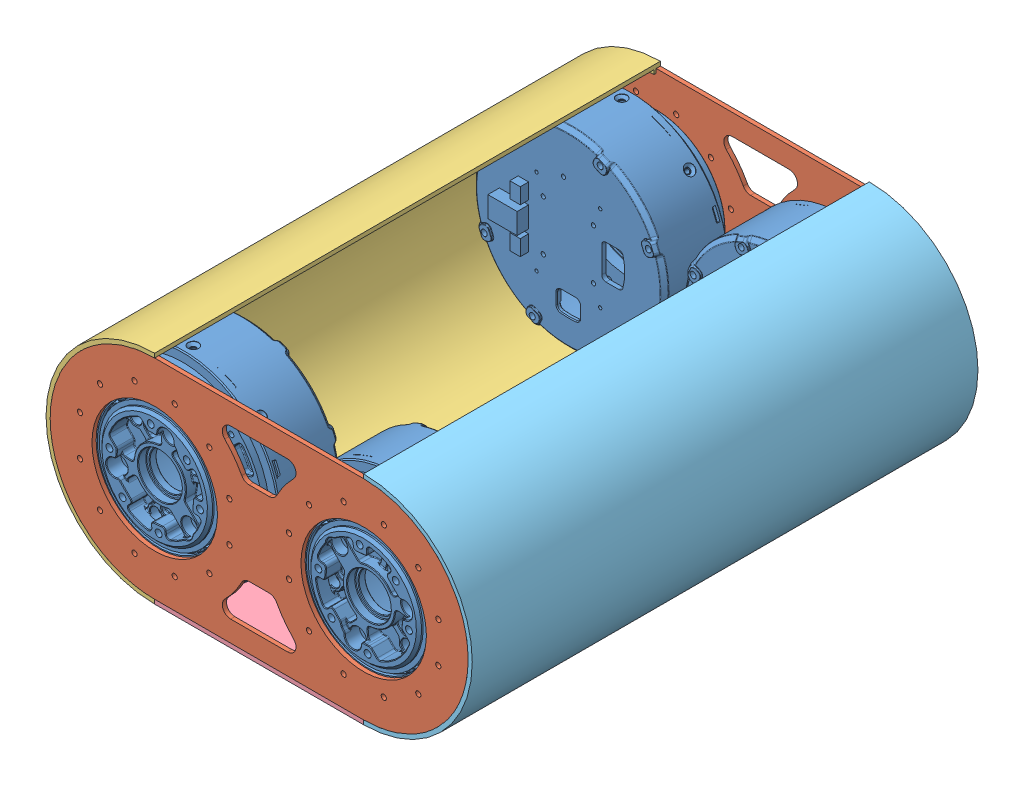
SolidWorks assembly 躯干框架, configuration 默认. Lengths in mm.
Overall size (230.12 130.12 242).
9 component instances, 5 part files, 22 mates.
Components (placement in the parent):
- 动力单元组件-1: 动力单元组件 [默认] at (100 52 -111) x (-0.707107 0.707107 0) z (0 0 -1) size (92.01 92.01 49.55)
- 动力单元组件-2: 动力单元组件 [默认] at (0 52 -111) x (0.707107 -0.707107 0) z (0 0 -1) size (92.01 92.01 49.55)
- 动力单元组件-3: 动力单元组件 [默认] at (0 52 111) x (0.707107 0.707107 0) z (0 0 1) size (92.01 92.01 49.55)
- 动力单元组件-4: 动力单元组件 [默认] at (100 52 111) x (-0.707107 -0.707107 0) z (0 0 1) size (92.01 92.01 49.55)
- 髋部碳板-1: 髋部碳板 [默认] at (50 52 -119) x (1 0 0) z (0 0 -1) size (200 100 2)
- 左壳-1: 左壳 [默认] at (50 52 -121) x (-1 0 0) z (0 0 1) size (52 104 242)
- 底盘碳板-1: 底盘碳板 [默认] at (50 0 0) size (100 2 242)
- 右壳-1: 右壳 [默认] at (50 52 -121) size (52 104 242)
- 髋部碳板-2: 髋部碳板 [默认] at (50 52 119) size (200 100 2)
Mates (geometry in assembly coordinates):
- 重合2: coincident anti-aligned: plane of 动力单元组件-1 through (123.3345 75.3345 -119) normal (0 0 -1); plane of 髋部碳板-1 through (0 52 -119) normal (0 0 1)
- 同心2: concentric aligned: circle of 动力单元组件-1; circle of 髋部碳板-1
- 同心3: concentric anti-aligned: circle of 髋部碳板-1; circle of 左壳-1
- 重合7: coincident aligned: circle of 髋部碳板-1; circle of 左壳-1
- 重合13: coincident aligned: line of 髋部碳板-1 through (100 2 -121) axis (-1 0 0); line of 底盘碳板-1 through (100 2 -121) axis (-1 0 0)
- 重合9: coincident anti-aligned: line of 左壳-1 through (0 0 121) axis (0 0 -1); line of 底盘碳板-1 through (0 0 -121) axis (0 0 1)
- 重合12: coincident aligned: plane of 左壳-1 through (0 52 121) normal (0 0 1); plane of 底盘碳板-1 through (100 2 121) normal (0 0 1)
- 重合15: coincident anti-aligned: plane of 髋部碳板-1 through (0 52 -119) normal (0 0 1); plane of 右壳-1 through (100 52 -119) normal (0 0 -1)
- 重合16: coincident aligned: circle of 髋部碳板-1; circle of 右壳-1
- 平行1: parallel anti-aligned: plane of 右壳-1 through (100 104 121) normal (-1 0 0)
- 平行2: parallel aligned: plane of 动力单元组件-1 through (133 52 -71.45) normal (1 0 0)
- 重合20: coincident anti-aligned: plane of 髋部碳板-1 through (0 52 -119) normal (0 0 1); plane of 动力单元组件-2 through (-23.3345 28.6655 -119) normal (0 0 -1)
- 同心4: concentric aligned: circle of 髋部碳板-1; circle of 动力单元组件-2
- 平行3: parallel anti-aligned: plane of 动力单元组件-2 through (-33 52 -71.45) normal (-1 0 0)
- 重合22: coincident anti-aligned: circle of 左壳-1; circle of 髋部碳板-2
- 重合23: coincident anti-aligned: circle of 右壳-1; circle of 髋部碳板-2
- 重合24: coincident anti-aligned: plane of 动力单元组件-3 through (-23.3345 75.3345 119) normal (0 0 1); plane of 髋部碳板-2 through (0 52 119) normal (0 0 -1)
- 重合25: coincident anti-aligned: plane of 动力单元组件-4 through (123.3345 28.6655 119) normal (0 0 1); plane of 髋部碳板-2 through (0 52 119) normal (0 0 -1)
- 同心5: concentric anti-aligned: cylinder of 动力单元组件-4; cylinder of 髋部碳板-2 through (100 52 121) axis (0 0 -1) radius 30
- 同心6: concentric anti-aligned: circle of 动力单元组件-3; cylinder of 髋部碳板-2 through (0 52 121) axis (0 0 -1) radius 30
- 平行4: parallel aligned: plane of 动力单元组件-4 through (133 52 71.45) normal (1 0 0)
- 平行5: parallel anti-aligned: plane of 动力单元组件-3 through (-33 52 71.45) normal (-1 0 0)
